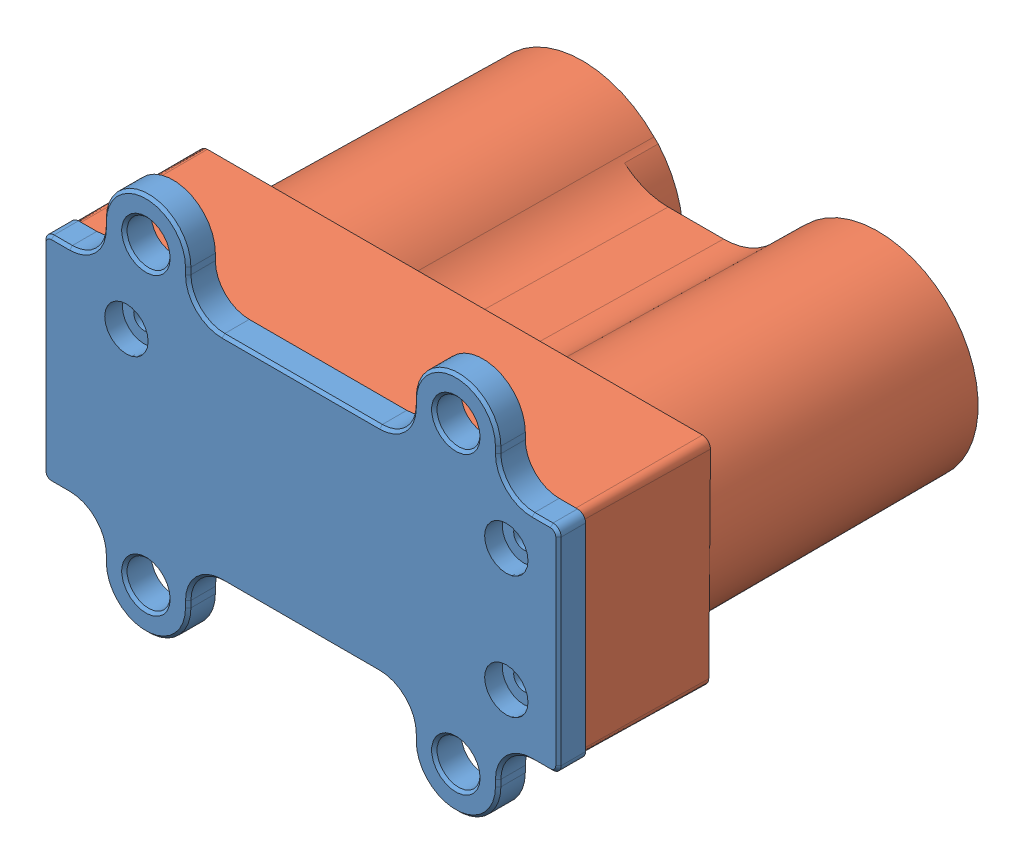
SolidWorks assembly LIDAR Lite-3 Assembly, configuration Default. Lengths in mm.
Overall size (48.26 35.56 39.93).
2 component instances, 2 part files, 0 mates.
Components (placement in the parent):
- LIDAR-Lite_Cover_RevC-1: LIDAR-Lite_Cover_RevC [Default] at (-4.1459 11.0528 31.9382) size (48.26 35.56 5.72)
- LIDAR-Lite_Housing_RevD-1: LIDAR-Lite_Housing_RevD [Default] at (43.8289 18.7606 33.9404) x (-1 0 0.000203) z (-0.000203 -0.008727 -0.999962) size (47.88 20.07 37.31)
